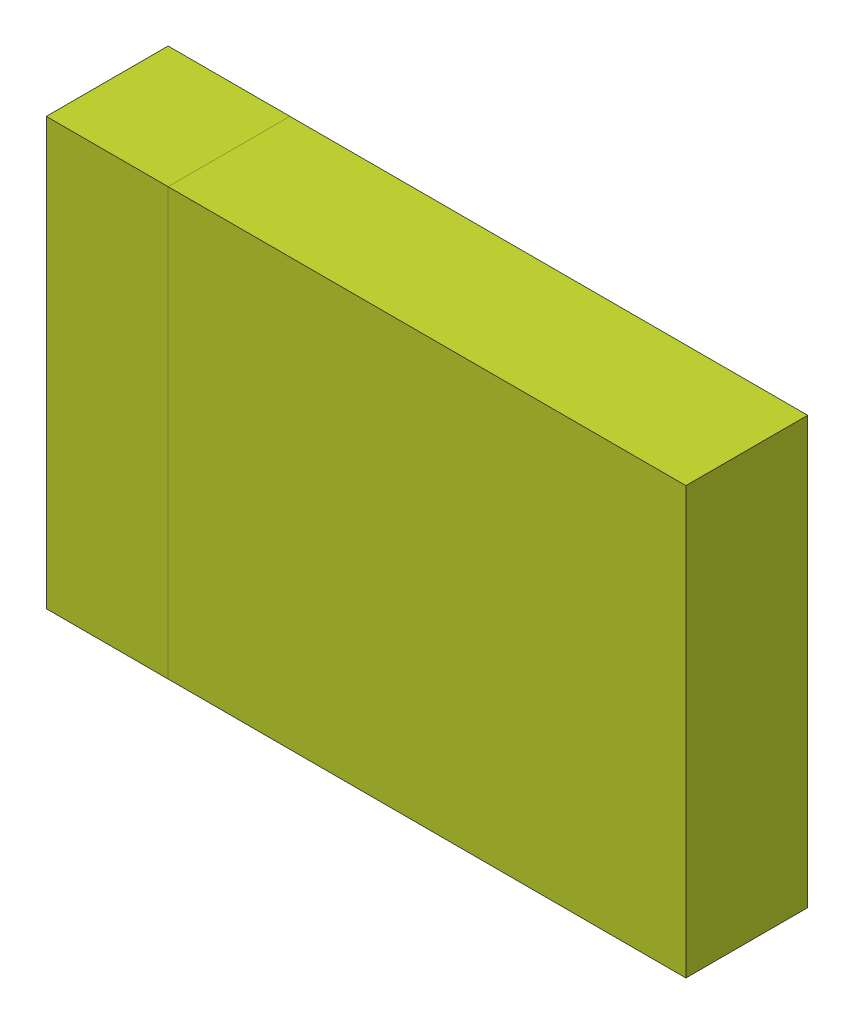
SolidWorks assembly 300mAh_Lipo_Battery, configuration Default. Lengths in mm.
Overall size (31.5 21 6).
9 component instances, 7 part files, 0 mates.
Components (placement in the parent):
- 300mAh_Lipo_Battery.step-1: 300mAh_Lipo_Battery.step [Default] at origin size (31.5 21 6)
  - Protection_IC.step-1: Protection_IC.step [Default] at origin size (3 12 2.85)
    - IC_board.step-1: IC_board.step [Default] at (-11.25 0 -3.75) x (0 1 0) z (0 0 1) size (12 3 1.5)
    - 101_smd_resistor.step-1: 101_smd_resistor.step [Default] at (-11.25 -5.5 3.75) x (0 -1 0) z (0 0 1) size (0.85 1.55 0.46)
    - 102_smd_resistor.step-1: 102_smd_resistor.step [Default] at (-11.25 5.5 3.75) x (0 1 0) z (0 0 1) size (0.85 1.55 0.46)
    - DW01-P.step-1: DW01-P.step [Default] at (-11.25 -1.5 3.9) x (0 1 0) z (0 0 1) size (2.8 2.9 1.35)
    - 8205A.step-1: 8205A.step [Default] at (-11.25 3 3.85) x (0 1 0) z (0 0 1) size (2.8 2.9 1.2)
    - smd_capacitor.step-1: smd_capacitor.step [Default] at (-11.25 -4 3.75) x (0 1 0) z (0 0 1) size (0.85 1.6 0.8)
  - Lipo_Body.step-1: Lipo_Body.step [Default] at origin size (31.5 21 6)
